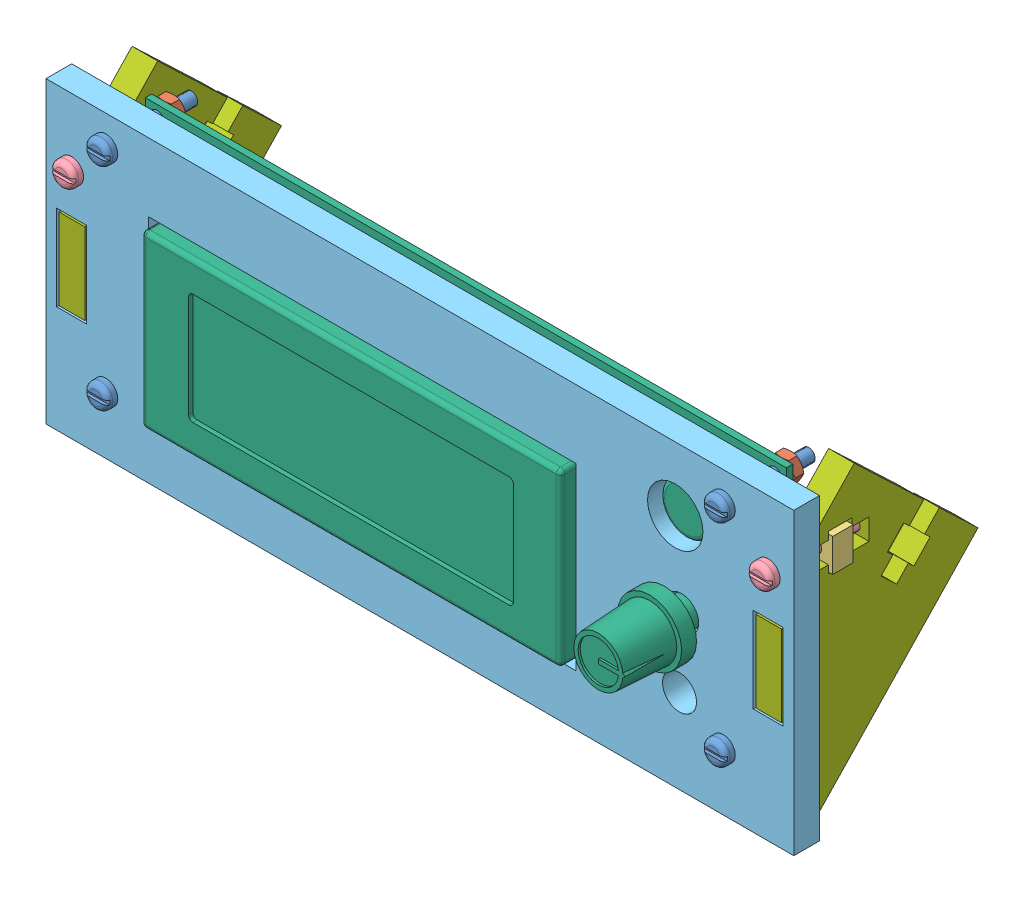
SolidWorks assembly screen, configuration Défaut. Lengths in mm.
Overall size (175 70 68.97).
20 component instances, 7 part files, 40 mates.
Components (placement in the parent):
- pan slot head_am-9: pan slot head_am [B18.6.7M - M3 x 0.5 x 20 Slotted PHMS --20N] at (-73.5 28 8.4) x (0 0 -1) z (1 0 0) size (22.4 5.6 5.6)
- pan slot head_am-11: pan slot head_am [B18.6.7M - M3 x 0.5 x 20 Slotted PHMS --20N] at (-73.5 -21.5 8.4) x (0 0 -1) z (1 0 0) size (22.4 5.6 5.6)
- pan slot head_am-12: pan slot head_am [B18.6.7M - M3 x 0.5 x 20 Slotted PHMS --20N] at (71 -21.5 8.4) x (0 0 -1) z (1 0 0) size (22.4 5.6 5.6)
- pan slot head_am-13: pan slot head_am [B18.6.7M - M3 x 0.5 x 20 Slotted PHMS --20N] at (71 28 8.4) x (0 0 -1) z (1 0 0) size (22.4 5.6 5.6)
- hex nut style 1_am-2: hex nut style 1_am [B18.2.4.1M - Hex nut, Style 1,  M3 x 0.5 --D-N] at (71 28 -9.9) x (0 1 0) z (0 0 -1) size (5.5 6.35 2.4)
- hex nut style 1_am-3: hex nut style 1_am [B18.2.4.1M - Hex nut, Style 1,  M3 x 0.5 --D-N] at (71 -21.5 -9.9) x (0 1 0) z (0 0 -1) size (5.5 6.35 2.4)
- hex nut style 1_am-4: hex nut style 1_am [B18.2.4.1M - Hex nut, Style 1,  M3 x 0.5 --D-N] at (-73.5 -21.5 -9.9) x (0.866025 0.5 0) z (0 0 -1) size (5.5 6.35 2.4)
- hex nut style 1_am-5: hex nut style 1_am [B18.2.4.1M - Hex nut, Style 1,  M3 x 0.5 --D-N] at (-73.5 28 -9.9) x (0.866025 0.5 0) z (0 0 -1) size (5.5 6.35 2.4)
- nut_fastener-33: nut_fastener [Défaut] at (81.5 19.4 -5) x (1 0 0) z (0 1 0) size (8.2 22.48 7.7)
  - nut-1: nut [Défaut] at origin size (8.2 4.8 7.7)
  - pan slot head_am (threaded)-1: pan slot head_am (threaded) [B18.6.7M - M3 x 0.5 x 20 Slotted PHMS --20N] at (0 -13.4 0) x (0 1 0) z (-1 0 0) size (22.48 5.6 5.6)
  - hex nut style 1_am-2: hex nut style 1_am [B18.2.4.1M - Hex nut, Style 1,  M3 x 0.5 --D-N] at (0 4.6 0) x (0 0 1) z (0 1 0) size (5.5 6.35 2.4)
- nut_fastener-34: nut_fastener [Défaut] at (-81.5 19.4 -5) x (1 0 0) z (0 1 0) size (8.2 22.48 7.7)
  - nut-1: nut [Défaut] at origin size (8.2 4.8 7.7)
  - pan slot head_am (threaded)-1: pan slot head_am (threaded) [B18.6.7M - M3 x 0.5 x 20 Slotted PHMS --20N] at (0 -13.4 0) x (0 1 0) z (-1 0 0) size (22.48 5.6 5.6)
  - hex nut style 1_am-2: hex nut style 1_am [B18.2.4.1M - Hex nut, Style 1,  M3 x 0.5 --D-N] at (0 4.6 0) x (0 0 1) z (0 1 0) size (5.5 6.35 2.4)
- screen_front-1: screen_front [Défaut] at origin size (175 70 6)
- RAMPS LCD2004-1: RAMPS LCD2004 [Défaut] at (-1.25 3.25 -7.5) size (150 62.75 33)
- screen_support-1: screen_support [left] at (-78.4 7 -40) x (-1 0 0) z (0 0.724138 -0.689655) size (6 40 58)
- screen_support-2: screen_support [right] at (84.6 7 -40) x (-1 0 0) z (0 0.724138 -0.689655) size (6 40 58)
Mates (geometry in assembly coordinates):
- Coaxiale1: concentric aligned: cylinder of screen_front-1 through (-73.5 28 0) axis (0 0 1) radius 2; cylinder of RAMPS LCD2004-1 through (-73.5 28 -6) axis (0 0 1) radius 1.6
- Coaxiale2: concentric aligned: cylinder of screen_front-1 through (71 -21.5 0) axis (0 0 1) radius 2; cylinder of RAMPS LCD2004-1 through (71 -21.5 -6) axis (0 0 1) radius 1.6
- Coïncidente2: coincident anti-aligned: plane of screen_front-1 through (0 0 0) normal (0 0 -1); plane of RAMPS LCD2004-1 through (-1.25 3.25 0) normal (0 0 1)
- Coïncidente3: coincident anti-aligned: plane of screen_front-1 through (0 0 0) normal (0 0 -1); plane of screen_support-1 through (-84.4 -9.5 0) normal (0 0 1)
- Parallèle1: parallel anti-aligned: plane of screen_support-1; plane of assembly through (0 0 0) normal (1 0 0)
- Coïncidente5: coincident aligned: line of screen_front-1 through (-87.5 -35 0) axis (1 0 0); line of screen_support-1 through (-84.4 -35 0) axis (1 0 0)
- Distance1: distance = 0.4 mm: line of screen_support-1 through (-78.4 -9.5 6) axis (0 1 0); line of screen_front-1 through (-78 -10 6) axis (0 1 0)
- Coïncidente6: coincident anti-aligned: plane of screen_front-1 through (0 0 0) normal (0 0 -1); plane of screen_support-2 through (78.6 -9.5 0) normal (0 0 1)
- Coïncidente7: coincident aligned: line of screen_front-1 through (-87.5 -35 0) axis (1 0 0); line of screen_support-2 through (78.6 -35 0) axis (1 0 0)
- Coaxiale10: concentric aligned: cylinder of screen_front-1 through (-73.5 28 0) axis (0 0 1) radius 2; cylinder of pan slot head_am-9 through (-73.5 28 33.8) axis (0 0 1) radius 2.8
- Coïncidente14: coincident anti-aligned: plane of screen_front-1 through (0 0 6) normal (0 0 1); plane of pan slot head_am-9 through (-73.5 29.5 6) normal (0 0 -1)
- Coaxiale12: concentric aligned: cylinder of screen_front-1 through (-73.5 -21.5 0) axis (0 0 1) radius 2; cylinder of pan slot head_am-11 through (-73.5 -21.5 33.8) axis (0 0 1) radius 2.8
- Coïncidente16: coincident anti-aligned: plane of screen_front-1 through (0 0 6) normal (0 0 1); plane of pan slot head_am-11 through (-73.5 -20 6) normal (0 0 -1)
- Coaxiale13: concentric aligned: cylinder of screen_front-1 through (71 -21.5 0) axis (0 0 1) radius 2; cylinder of pan slot head_am-12 through (71 -21.5 33.8) axis (0 0 1) radius 2.8
- Coïncidente17: coincident anti-aligned: plane of screen_front-1 through (0 0 6) normal (0 0 1); plane of pan slot head_am-12 through (71 -20 6) normal (0 0 -1)
- Coaxiale14: concentric aligned: cylinder of screen_front-1 through (71 28 0) axis (0 0 1) radius 2; cylinder of pan slot head_am-13 through (71 28 33.8) axis (0 0 1) radius 2.8
- Coïncidente18: coincident anti-aligned: plane of screen_front-1 through (0 0 6) normal (0 0 1); plane of pan slot head_am-13 through (71 29.5 6) normal (0 0 -1)
- Coaxiale16: concentric anti-aligned: cylinder of pan slot head_am-13 through (71 28 33.8) axis (0 0 1) radius 1.5; cylinder of hex nut style 1_am-2 through (71 28 15.1375) axis (0 0 -1) radius 1.5
- Coaxiale17: concentric anti-aligned: cylinder of pan slot head_am-12 through (71 -21.5 33.8) axis (0 0 1) radius 1.5; cylinder of hex nut style 1_am-3 through (71 -21.5 15.1375) axis (0 0 -1) radius 1.5
- Coaxiale18: concentric anti-aligned: cylinder of pan slot head_am-11 through (-73.5 -21.5 33.8) axis (0 0 1) radius 1.5; cylinder of hex nut style 1_am-4 through (-73.5 -21.5 15.1375) axis (0 0 -1) radius 1.5
- Coaxiale19: concentric anti-aligned: cylinder of pan slot head_am-9 through (-73.5 28 33.8) axis (0 0 1) radius 1.5; cylinder of hex nut style 1_am-5 through (-73.5 28 15.1375) axis (0 0 -1) radius 1.5
- Parallèle2: parallel aligned: plane of hex nut style 1_am-2 through (69.4123 25.25 -7.5) normal (-0.866025 -0.5 0); plane of hex nut style 1_am-3 through (69.4123 -24.25 -7.5) normal (-0.866025 -0.5 0)
- Parallèle4: parallel aligned: plane of hex nut style 1_am-4 through (-75.0877 -18.75 -7.5) normal (0 1 0); plane of hex nut style 1_am-5 through (-75.0877 30.75 -7.5) normal (0 1 0)
- Parallèle5: parallel aligned: plane of hex nut style 1_am-3 through (67.8246 -21.5 -7.5) normal (-0.866025 0.5 0); plane of hex nut style 1_am-4 through (-76.6754 -21.5 -7.5) normal (-0.866025 0.5 0)
- Coïncidente25: coincident anti-aligned: plane of RAMPS LCD2004-1 through (-1.25 3.25 -7.5) normal (0 0 -1); plane of hex nut style 1_am-2 through (74.1754 28 -7.5) normal (0 0 1)
- Coïncidente26: coincident anti-aligned: plane of RAMPS LCD2004-1 through (-1.25 3.25 -7.5) normal (0 0 -1); plane of hex nut style 1_am-3 through (74.1754 -21.5 -7.5) normal (0 0 1)
- Coïncidente27: coincident anti-aligned: plane of RAMPS LCD2004-1 through (-1.25 3.25 -7.5) normal (0 0 -1); plane of hex nut style 1_am-5 through (-71.9123 25.25 -7.5) normal (0 0 1)
- Coïncidente28: coincident anti-aligned: plane of RAMPS LCD2004-1 through (-1.25 3.25 -7.5) normal (0 0 -1); plane of hex nut style 1_am-4 through (-71.9123 -24.25 -7.5) normal (0 0 1)
- Parallèle6: parallel aligned: plane of screen_front-1 through (-87.5 35 6) normal (0 1 0); plane of hex nut style 1_am-2 through (72.5877 30.75 -7.5) normal (0 1 0)
- Coaxiale20: concentric aligned: cylinder of screen_front-1 through (81.5 19.4 0) axis (0 0 1) radius 2; cylinder of nut_fastener-33/pan slot head_am (threaded)-1 through (81.5 19.4 33.8) axis (0 0 1) radius 1.5
- Coïncidente30: coincident anti-aligned: plane of screen_support-2 through (84.6 7 -5) normal (0 0 -1); plane of nut_fastener-33/nut-1 through (81.5 19.4 -5) normal (0 0 1)
- Parallèle7: parallel aligned: plane of screen_support-2 through (84.6 7 -40) normal (1 0 0); plane of nut_fastener-33/nut-1 through (85.6 19.4 -9.8) normal (1 0 0)
- Coaxiale21: concentric aligned: cylinder of screen_front-1 through (-81.5 19.4 0) axis (0 0 1) radius 2; cylinder of nut_fastener-34/pan slot head_am (threaded)-1 through (-81.5 19.4 33.8) axis (0 0 1) radius 1.5
- Coïncidente31: coincident anti-aligned: plane of screen_support-1 through (-78.4 7 -5) normal (0 0 -1); plane of nut_fastener-34/nut-1 through (-81.5 19.4 -5) normal (0 0 1)
- Parallèle8: parallel aligned: plane of screen_support-1 through (-84.4 7 -40) normal (-1 0 0); plane of nut_fastener-34/nut-1 through (-85.6 19.4 -9.8) normal (-1 0 0)
- Parallèle9: parallel aligned: line of pan slot head_am-9 through (-70.856 28.5 7.7) axis (-1 0 0); line of pan slot head_am-11 through (-70.856 -21 7.7) axis (-1 0 0)
- Parallèle10: parallel aligned: line of pan slot head_am-12 through (73.644 -21 7.7) axis (-1 0 0); line of pan slot head_am-13 through (73.644 28.5 7.7) axis (-1 0 0)
- Parallèle11: parallel aligned: line of pan slot head_am-11 through (-70.856 -21 7.7) axis (-1 0 0); line of pan slot head_am-12 through (73.644 -21 7.7) axis (-1 0 0)
- Parallèle12: parallel anti-aligned: line of screen_front-1 through (-87.5 -35 6) axis (1 0 0); line of pan slot head_am-11 through (-70.856 -21 7.7) axis (-1 0 0)
- Distance3: distance = 0.4 mm: line of screen_support-2 through (84.6 -9.5 6) axis (0 1 0); line of screen_front-1 through (85 10 6) axis (0 -1 0)
